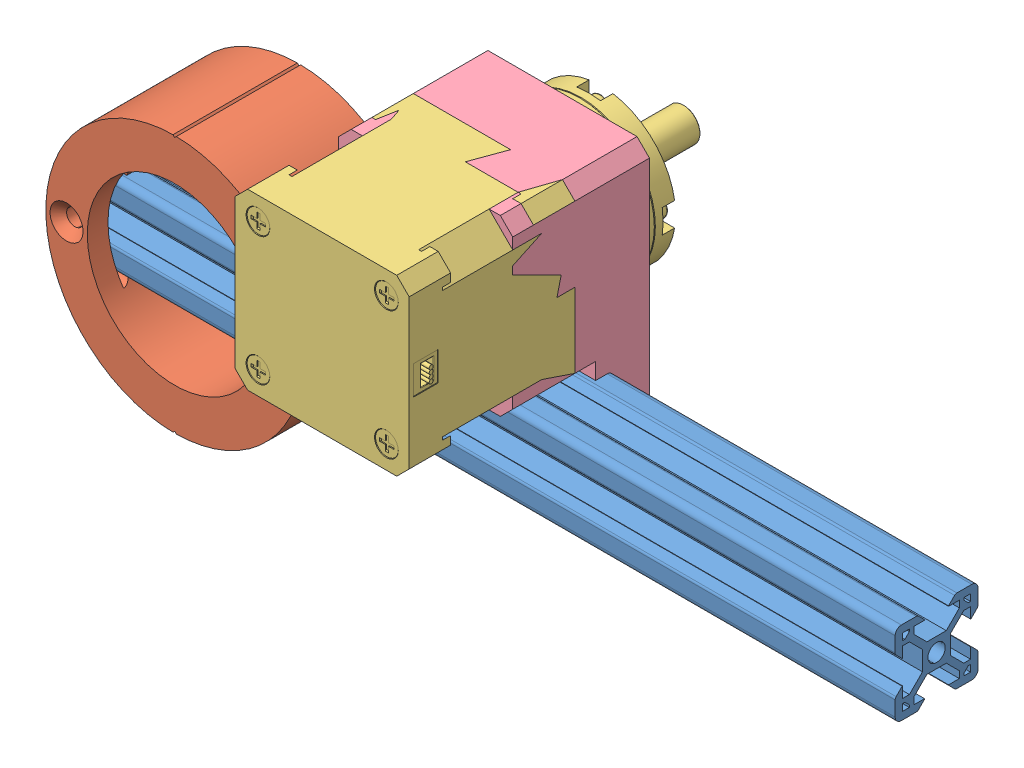
SolidWorks assembly PantherArm-C, configuration Standard. Lengths in mm.
Overall size (222.61 84.1 87.3).
6 component instances, 6 part files, 10 mates.
Components (placement in the parent):
- V-Slot20x20-1: V-Slot20x20 [200] at (-36.8905 -3.5845 0) x (0 0 -1) z (1 0 0) size (20 20 200)
- InnerCollector-1: InnerCollector [Standard] at (-205.7905 -3.5845 0) size (107.29 62.2 30)
- Nema17Geared-1: Nema17Geared [Standard] at (-145.8905 28.4155 -0.7) x (1 0 0) z (0 0 -1) size (42.88 42 87.3)
- GearedStepperBracket-1: GearedStepperBracket [Standard] at (-145.8905 28.4155 -18.7) size (42 63 33)
- V-Slot-T-Nut-1: V-Slot-T-Nut [Default] at (-178.2905 -8.5835 -8.2) size (15 10 3.3)
- 5x8SocketHeadScrew-1: 5x8SocketHeadScrew [5mm x 8mm Low Profile] at (-170.7905 -3.5845 -13.75) x (0 0 1) z (-1 0 0) size (10.1 9.5 9.5)
Mates (geometry in assembly coordinates):
- Deckungsgleich31: coincident aligned: plane of V-Slot20x20-1; plane of InnerCollector-1 through (-205.7905 -3.5845 0) normal (0 1 0)
- Deckungsgleich32: coincident anti-aligned: plane of V-Slot20x20-1 through (-36.8905 -3.5845 0) normal (0 0 -1); plane of InnerCollector-1 through (-205.7905 -3.5845 0) normal (0 0 1)
- Tangential2: tangent aligned: plane of V-Slot20x20-1 through (-236.8905 -8.4917 9.21) normal (-1 0 0); cylinder of InnerCollector-1 through (-205.7905 -3.5845 15) axis (0 0 -1) radius 31.1
- Konzentrisch8: concentric anti-aligned: cylinder of Nema17Geared-1 through (-145.8905 28.4155 -22.875) axis (0 0 1) radius 18; cylinder of GearedStepperBracket-1 through (-145.8905 28.4155 -5.7) axis (0 0 -1) radius 18.1
- Abstand1: distance = 20 mm anti-aligned: plane of GearedStepperBracket-1 through (-145.8905 28.4155 14.3) normal (0 0 1); plane of Nema17Geared-1 through (-145.8905 28.4155 -5.7) normal (0 0 -1)
- Deckungsgleich36: coincident aligned: plane of V-Slot20x20-1 through (-236.8905 -13.5845 -4.9072) normal (0 -1 0); plane of GearedStepperBracket-1 through (-166.8905 -13.5845 -5.7) normal (0 -1 0)
- Deckungsgleich37: coincident aligned: plane of Nema17Geared-1; plane of GearedStepperBracket-1 through (-145.8905 28.4155 -18.7) normal (1 0 0)
- Deckungsgleich39: coincident anti-aligned: plane of V-Slot20x20-1 through (-236.8905 -0.6945 -8.2) normal (0 0 1); plane of V-Slot-T-Nut-1 through (-178.2905 -8.5835 -8.2) normal (0 0 -1)
- Parallel2: parallel aligned: plane of V-Slot20x20-1 through (-236.8905 -8.4917 9.21) normal (-1 0 0); plane of V-Slot-T-Nut-1 through (-178.2905 -8.5835 -6.55) normal (-1 0 0)
- Parallel3: parallel aligned: plane of V-Slot20x20-1 through (-236.8905 -8.4917 9.21) normal (-1 0 0); plane of 5x8SocketHeadScrew-1 through (-169.2905 -2.7184 -12.75) normal (-1 0 0)
